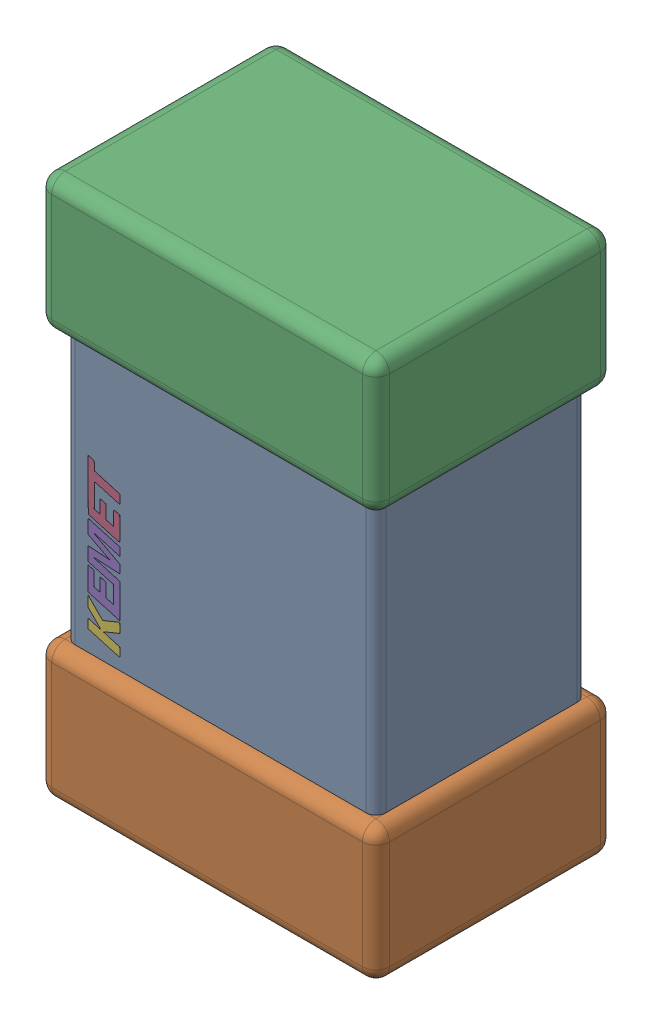
SolidWorks assembly C10.step, configuration Default. Lengths in mm.
Overall size (1.25 2 0.88).
3 component instances, 3 part files, 0 mates.
Components (placement in the parent):
- Cap_KEMET_C0805C472J3HAC_eec.step-1: Cap_KEMET_C0805C472J3HAC_eec.step [Default] at (50.756 65.924 0) x (0 1 0) z (0 0 1) size (1 1.15 0.78)
- Cap_KEMET_C0805C472J3HAC_eec-7.step-1: Cap_KEMET_C0805C472J3HAC_eec-7.step [Default] at (50.756 65.924 0) x (0 1 0) z (0 0 1) size (2 1.25 0.88)
- Cap_KEMET_C0805C472J3HAC_eec-8.step-1: Cap_KEMET_C0805C472J3HAC_eec-8.step [Default] at (50.756 65.924 0) x (0 1 0) z (0 0 1) size (0.59 0.12 0)
